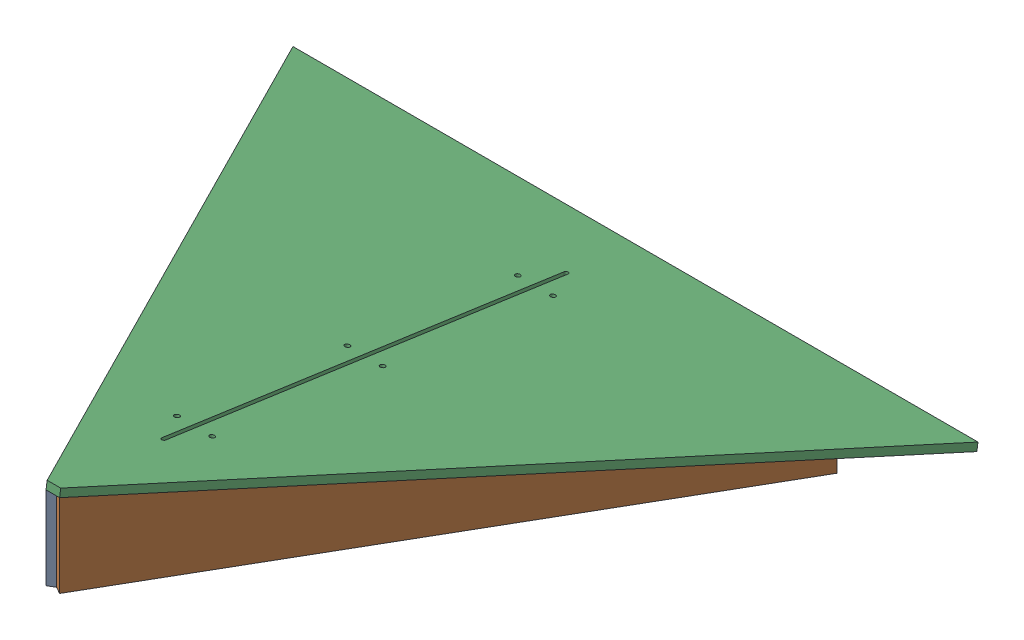
SolidWorks assembly GE-16189_ASM, configuration Default. Lengths in mm.
Overall size (1112.3 147.28 946.07).
3 component instances, 3 part files, 0 mates.
Components (placement in the parent):
- GE-16189-02-1: GE-16189-02 [Default] at origin size (473.08 134.72 806.69)
- GE-16189-03-1: GE-16189-03 [Default] at (473.075 0 -3402.4927) x (-1 0 0) z (0 0 -1) size (473.08 134.72 806.69)
- GE-16189-01-1: GE-16189-01 [Default] at (473.0748 134.7119 -3421.6102) x (-1 0 -0.000039) z (0.000039 -0.141244 -0.989975) size (1112.27 12.7 953.75)
